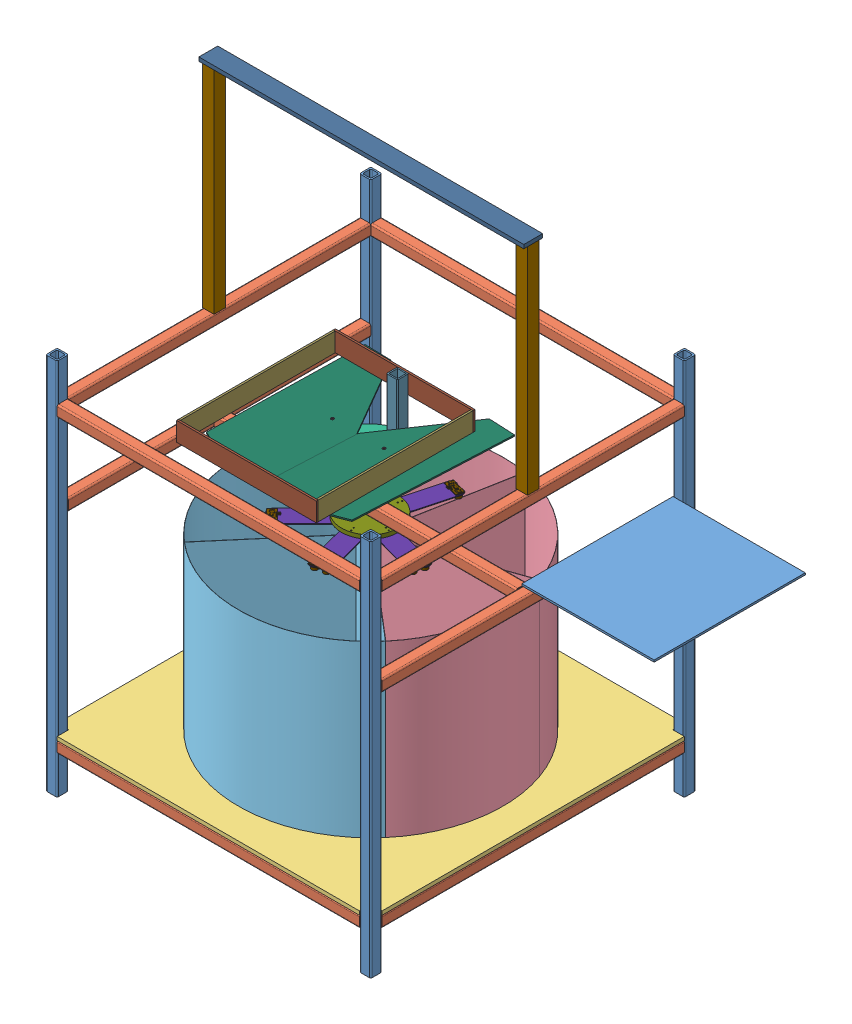
SolidWorks assembly Assem1, configuration Default. Lengths in mm.
Overall size (1243.66 1480 923.66).
50 component instances, 19 part files, 136 mates.
Components (placement in the parent):
- Bar_2-1: Bar_2 [Default] at (302.6173 -40.2152 847.0391) size (30 1000 30)
- Bar_2-2: Bar_2 [Default] at (302.6173 -40.2152 17.0391) size (30 1000 30)
- bar-2: bar [Default] at (1117.6173 74.7848 847.0391) x (0 1 0) z (0 0 1) size (30 800 30)
- Bar_2-5: Bar_2 [Default] at (1132.6173 -40.2152 847.0391) x (-1 0 0) z (0 0 -1) size (30 1000 30)
- bar-6: bar [Default] at (1132.6173 74.7848 32.0391) x (0 1 0) z (1 0 0) size (30 800 30)
- Bar_2-8: Bar_2 [Default] at (1132.6173 -40.2152 17.0391) x (0 0 1) z (-1 0 0) size (30 1000 30)
- bar-8: bar [Default] at (302.6173 74.7848 32.0391) x (0 -1 0) z (-1 0 0) size (30 800 30)
- bar-10: bar [Default] at (317.6173 74.7848 17.0391) x (0 1 0) z (0 0 -1) size (30 800 30)
- bar-12: bar [Default] at (317.6173 844.7848 847.0391) x (0 1 0) z (0 0 -1) size (30 800 30)
- bar-14: bar [Default] at (302.6173 844.7848 32.0391) x (0 1 0) z (1 0 0) size (30 800 30)
- bar-16: bar [Default] at (317.6173 844.7848 17.0391) x (0 1 0) z (0 0 -1) size (30 800 30)
- bar-18: bar [Default] at (1132.6173 844.7848 32.0391) x (0 1 0) z (1 0 0) size (30 800 30)
- bar-20: bar [Default] at (1117.6173 74.7848 287.0391) x (0 1 0) z (0 0 1) size (30 800 30)
- bar-22: bar [Default] at (1117.6173 74.7848 577.0391) x (0 -1 0) z (0 0 -1) size (30 800 30)
- bar-24: bar [Default] at (302.6173 614.7848 32.0391) x (0 1 0) z (1 0 0) size (30 800 30)
- bar-26: bar [Default] at (1132.6173 614.7848 832.0391) x (0 -1 0) z (1 0 0) size (30 800 30)
- sheet-1: sheet [Default] at (717.6173 89.7848 432.0391) size (860 10 860)
- Bin_Compart-1: Bin_Compart [Default] at (717.6173 99.7848 432.0391) x (0.181338 0 -0.983421) z (0.983421 0 0.181338) size (350.18 450 336.32)
- Bin_Compart-2: Bin_Compart [Default] at (717.6173 99.7848 432.0391) x (-0.942336 0 0.334667) z (-0.334667 0 -0.942336) size (350.18 450 336.32)
- Bin_Compart-3: Bin_Compart [Default] at (717.6173 99.7848 432.0391) x (-0.760999 0 -0.648753) z (0.648753 0 -0.760999) size (350.18 450 336.32)
- Part2-2: Part2 [Default] at (717.6173 99.7848 432.0391) x (-0.760999 0 -0.648753) z (0.648753 0 -0.760999) size (350.18 450 350.18)
- Disc-2: Disc [Default] at (716.3673 725.3848 433.2891) size (200 5 200)
- bar-27: bar [Default] at (317.6173 614.7848 432.0391) x (0 0 1) z (0 1 0) size (30 800 30)
- Stepper motor NEMA 23HS7430-1: Stepper motor NEMA 23HS7430 [По умолчанию] at (716.3673 709.7848 433.2891) x (1 0 0) z (0 -1 0) size (58.4 56.4 95.6)
- mount-1: mount [Default] at (742.6173 634.7848 457.0391) x (0 0 1) z (0 -1 0) size (50 50 5)
- bAR1-1: bAR1 [Default] at (1132.6173 1173.2848 432.0391) x (1 0 0) z (0 0 -1) size (30 570 30)
- bAR1-2: bAR1 [Default] at (302.6173 1173.2848 432.0391) x (1 0 0) z (0 0 -1) size (30 570 30)
- camera mount-1: camera mount [Default] at (287.6173 1439.7848 457.0391) x (0 0 -1) z (-1 0 0) size (50 10 860)
- Wall_1-1: Wall_1 [Default] at (530.859 829.3848 339.3531) x (0 -1 0) z (-1 0 0) size (50 5 370)
- wall_2-1: wall_2 [Default] at (535.859 879.3848 754.3531) x (1 0 0) z (0 0 -1) size (5 50 410)
- wall_2-2: wall_2 [Default] at (900.859 879.3848 754.3531) x (1 0 0) z (0 0 -1) size (5 50 410)
- Wall_1-2: Wall_1 [Default] at (900.859 829.3848 759.3531) x (0 -1 0) z (1 0 0) size (50 5 370)
- Part2-3: Part2 [Default] at (717.6173 99.7848 432.0391) x (0.648753 0 -0.760999) z (0.760999 0 0.648753) size (350.18 450 350.18)
- ft6560m 60kg.cm.step-5: ft6560m 60kg.cm.step [Default] at (784.8673 771.3848 446.4174) x (-1 0 0) z (0 0 -1) size (30 64 82)
- ft6560m 60kg.cm.step-6: ft6560m 60kg.cm.step [Default] at (647.8673 771.3848 446.4174) x (-1 0 0) z (0 0 -1) size (30 64 82)
- wall holder-2: wall holder [Default] at (715.859 879.3848 359.3531) x (0 0 -1) z (-1 0 0) size (30 150 30)
- flaps-3: flaps [Default] at (824.4567 792.4598 498.9645) x (-0.998861 0 -0.047712) z (0.047712 0 -0.998861) size (200 3.5 456.77)
- flaps-4: flaps [Default] at (605.9536 792.8098 496.1488) x (0.999772 0 0.021336) z (0.021336 0 -0.999772) size (200 3.5 456.77)
- UltraHolder-1: UltraHolder [Default] at (716.3673 589.7848 433.2891) x (-0.981254 0 0.19272) z (-0.19272 0 -0.981254) size (150 10 150)
- HC-SR04 Ultrasonic Sensor Holder-2: HC-SR04 Ultrasonic Sensor Holder [Default] at (733.5127 587.7848 594.4219) x (0 1 0) z (0.966613 0 -0.256242) size (2 150 50)
- HC-SR04 Ultrasonic Sensor Holder-3: HC-SR04 Ultrasonic Sensor Holder [Default] at (864.4113 587.7848 498.71) x (0 1 0) z (0.261394 0 -0.965232) size (2 150 50)
- HC-SR04 Ultrasonic Sensor Holder-4: HC-SR04 Ultrasonic Sensor Holder [Default] at (585.2984 587.7848 528.3994) x (0 1 0) z (0.705219 0 0.70899) size (2 150 50)
- HC-SR04 Ultrasonic Sensor Holder-5: HC-SR04 Ultrasonic Sensor Holder [Default] at (782.3211 587.7848 285.3868) x (0 1 0) z (-0.965232 0 -0.261394) size (2 150 50)
- HC-SR04 Ultrasonic Sensor Holder-7: HC-SR04 Ultrasonic Sensor Holder [Default] at (568.9979 587.7848 367.477) x (0 1 0) z (-0.261394 0 0.965232) size (2 150 50)
- HCSR04 Ultrasonic Sensor-1: HCSR04 Ultrasonic Sensor [Default] at (764.2023 591.2848 256.6516) x (-0.965232 0 -0.261394) z (0 -1 0) size (45 26.6 18)
- HCSR04 Ultrasonic Sensor-2: HCSR04 Ultrasonic Sensor [Default] at (540.2627 591.2848 385.5958) x (-0.261394 0 0.965232) z (0 -1 0) size (45 26.6 18)
- HCSR04 Ultrasonic Sensor-4: HCSR04 Ultrasonic Sensor [Default] at (586.6221 591.2848 562.3442) x (0.705219 0 0.70899) z (0 -1 0) size (45 26.6 18)
- HCSR04 Ultrasonic Sensor-6: HCSR04 Ultrasonic Sensor [Default] at (763.5715 591.2848 610.2479) x (0.966613 0 -0.256242) z (0 -1 0) size (45 26.6 18)
- HCSR04 Ultrasonic Sensor-8: HCSR04 Ultrasonic Sensor [Default] at (893.1465 591.2848 480.5912) x (0.261394 0 -0.965232) z (0 -1 0) size (45 26.6 18)
- electronic holder-1: electronic holder [Default] at (1310.1173 632.0348 212.0391) size (350 5 400)
Mates (geometry in assembly coordinates):
- Coincident1: coincident anti-aligned: plane of Bar_2-1 through (317.6173 959.7848 836.0391) normal (1 0 0); plane of bar-2 through (317.6173 85.7848 836.0391) normal (-1 0 0)
- Width1: width anti-aligned: plane of bar-2 through (317.6173 85.7848 862.0391) normal (0 0 1); plane of bar-2 through (317.6173 85.7848 832.0391) normal (0 0 -1); plane of Bar_2-1 through (313.6173 959.7848 832.0391) normal (0 0 -1); plane of Bar_2-1 through (313.6173 959.7848 862.0391) normal (0 0 1)
- Distance1: distance = 100 mm: line of bar-2 through (317.6173 59.7848 836.0391) axis (0 0 1); line of Bar_2-1 through (317.6173 -40.2152 858.0391) axis (0 0 -1)
- Coincident2: coincident anti-aligned: plane of bar-2 through (1117.6173 85.7848 836.0391) normal (1 0 0); plane of Bar_2-5 through (1117.6173 959.7848 858.0391) normal (-1 0 0)
- Width2: width anti-aligned: plane of bar-2 through (317.6173 85.7848 832.0391) normal (0 0 -1); plane of bar-2 through (317.6173 85.7848 862.0391) normal (0 0 1); plane of Bar_2-5 through (1121.6173 959.7848 862.0391) normal (0 0 1); plane of Bar_2-5 through (1121.6173 959.7848 832.0391) normal (0 0 -1)
- Distance2: distance = 100 mm: line of bar-2 through (1117.6173 59.7848 836.0391) axis (0 0 1); line of Bar_2-5 through (1117.6173 -40.2152 836.0391) axis (0 0 1)
- Coincident5: coincident anti-aligned: plane of Bar_2-5 through (1121.6173 959.7848 832.0391) normal (0 0 -1); plane of bar-6 through (1121.6173 85.7848 832.0391) normal (0 0 1)
- Width3: width anti-aligned: plane of bar-6 through (1147.6173 85.7848 832.0391) normal (1 0 0); plane of bar-6 through (1117.6173 85.7848 832.0391) normal (-1 0 0); plane of Bar_2-5 through (1117.6173 959.7848 858.0391) normal (-1 0 0); plane of Bar_2-5 through (1147.6173 959.7848 858.0391) normal (1 0 0)
- Distance3: distance = 100 mm: line of bar-6 through (1121.6173 59.7848 832.0391) axis (1 0 0); line of Bar_2-5 through (1143.6173 -40.2152 832.0391) axis (-1 0 0)
- Coincident6: coincident anti-aligned: plane of bar-6 through (1121.6173 85.7848 32.0391) normal (0 0 -1); plane of Bar_2-8 through (1143.6173 959.7848 32.0391) normal (0 0 1)
- Width4: width anti-aligned: plane of bar-6 through (1117.6173 85.7848 832.0391) normal (-1 0 0); plane of bar-6 through (1147.6173 85.7848 832.0391) normal (1 0 0); plane of Bar_2-8 through (1147.6173 959.7848 28.0391) normal (1 0 0); plane of Bar_2-8 through (1117.6173 959.7848 28.0391) normal (-1 0 0)
- Distance6: distance = 100 mm: line of Bar_2-8 through (1121.6173 -40.2152 32.0391) axis (1 0 0); line of bar-6 through (1121.6173 59.7848 32.0391) axis (1 0 0)
- Coincident8: coincident anti-aligned: plane of Bar_2-1 through (313.6173 959.7848 832.0391) normal (0 0 -1); plane of bar-8 through (313.6173 63.7848 832.0391) normal (0 0 1)
- Width5: width anti-aligned: plane of bar-8 through (287.6173 63.7848 832.0391) normal (-1 0 0); plane of bar-8 through (317.6173 63.7848 832.0391) normal (1 0 0); plane of Bar_2-1 through (317.6173 959.7848 836.0391) normal (1 0 0); plane of Bar_2-1 through (287.6173 959.7848 836.0391) normal (-1 0 0)
- Distance7: distance = 100 mm: line of bar-8 through (291.6173 59.7848 832.0391) axis (1 0 0); line of Bar_2-1 through (313.6173 -40.2152 832.0391) axis (-1 0 0)
- Coincident10: coincident anti-aligned: plane of Bar_2-2 through (313.6173 959.7848 32.0391) normal (0 0 1); plane of bar-8 through (313.6173 63.7848 32.0391) normal (0 0 -1)
- Width6: width anti-aligned: plane of bar-8 through (287.6173 63.7848 832.0391) normal (-1 0 0); plane of bar-8 through (317.6173 63.7848 832.0391) normal (1 0 0); plane of Bar_2-2 through (317.6173 959.7848 6.0391) normal (1 0 0); plane of Bar_2-2 through (287.6173 959.7848 6.0391) normal (-1 0 0)
- Distance8: distance = 100 mm: line of bar-8 through (291.6173 59.7848 32.0391) axis (1 0 0); line of Bar_2-2 through (291.6173 -40.2152 32.0391) axis (1 0 0)
- Coincident11: coincident anti-aligned: plane of Bar_2-8 through (1117.6173 959.7848 28.0391) normal (-1 0 0); plane of bar-10 through (1117.6173 85.7848 28.0391) normal (1 0 0)
- Width7: width anti-aligned: plane of bar-10 through (1117.6173 85.7848 2.0391) normal (0 0 -1); plane of bar-10 through (1117.6173 85.7848 32.0391) normal (0 0 1); plane of Bar_2-8 through (1143.6173 959.7848 32.0391) normal (0 0 1); plane of Bar_2-8 through (1143.6173 959.7848 2.0391) normal (0 0 -1)
- Distance9: distance = 100 mm: line of bar-10 through (1117.6173 59.7848 28.0391) axis (0 0 -1); line of Bar_2-8 through (1117.6173 -40.2152 6.0391) axis (0 0 1)
- Coincident14: coincident anti-aligned: plane of Bar_2-5 through (1117.6173 959.7848 858.0391) normal (-1 0 0); plane of bar-12 through (1117.6173 855.7848 858.0391) normal (1 0 0)
- Width9: width anti-aligned: plane of bar-12 through (1117.6173 855.7848 832.0391) normal (0 0 -1); plane of Bar_2-5 through (1117.6173 855.7848 862.0391) normal (0 0 1); plane of bar-12 through (1121.6173 959.7848 862.0391) normal (0 0 1); plane of Bar_2-5 through (1121.6173 959.7848 832.0391) normal (0 0 -1)
- Distance11: distance = 100 mm: line of bar-12 through (1117.6173 859.7848 836.0391) axis (0 0 1); line of Bar_2-5 through (1117.6173 959.7848 836.0391) axis (0 0 1)
- Coincident15: coincident anti-aligned: plane of Bar_2-1 through (313.6173 959.7848 832.0391) normal (0 0 -1); plane of bar-14 through (291.6173 855.7848 832.0391) normal (0 0 1)
- Width10: width anti-aligned: plane of bar-14 through (317.6173 855.7848 832.0391) normal (1 0 0); plane of Bar_2-1 through (287.6173 855.7848 832.0391) normal (-1 0 0); plane of bar-14 through (287.6173 959.7848 836.0391) normal (-1 0 0); plane of Bar_2-1 through (317.6173 959.7848 836.0391) normal (1 0 0)
- Distance12: distance = 100 mm: line of bar-14 through (313.6173 859.7848 832.0391) axis (-1 0 0); line of Bar_2-1 through (313.6173 959.7848 832.0391) axis (-1 0 0)
- Coincident16: coincident anti-aligned: plane of Bar_2-8 through (1117.6173 959.7848 28.0391) normal (-1 0 0); plane of bar-16 through (1117.6173 855.7848 28.0391) normal (1 0 0)
- Width11: width anti-aligned: plane of bar-16 through (1117.6173 855.7848 2.0391) normal (0 0 -1); plane of Bar_2-8 through (1117.6173 855.7848 32.0391) normal (0 0 1); plane of bar-16 through (1143.6173 959.7848 32.0391) normal (0 0 1); plane of Bar_2-8 through (1143.6173 959.7848 2.0391) normal (0 0 -1)
- Distance14: distance = 100 mm: point of bar-16; line of Bar_2-8 through (1117.6173 959.7848 6.0391) axis (0 0 1)
- Coincident18: coincident anti-aligned: plane of Bar_2-5 through (1121.6173 959.7848 832.0391) normal (0 0 -1); plane of bar-18 through (1121.6173 855.7848 832.0391) normal (0 0 1)
- Width13: width anti-aligned: plane of bar-18 through (1147.6173 855.7848 832.0391) normal (1 0 0); plane of Bar_2-5 through (1117.6173 855.7848 832.0391) normal (-1 0 0); plane of bar-18 through (1117.6173 959.7848 858.0391) normal (-1 0 0); plane of Bar_2-5 through (1147.6173 959.7848 858.0391) normal (1 0 0)
- Distance15: distance = 100 mm: line of bar-18 through (1143.6173 859.7848 832.0391) axis (-1 0 0); line of Bar_2-5 through (1143.6173 959.7848 832.0391) axis (-1 0 0)
- Coincident20: coincident anti-aligned: plane of bar-8 through (317.6173 63.7848 832.0391) normal (1 0 0); plane of bar-20 through (317.6173 85.7848 276.0391) normal (-1 0 0)
- Width15: width aligned: plane of bar-20 through (317.6173 89.7848 276.0391) normal (0 1 0); plane of bar-8 through (317.6173 59.7848 276.0391) normal (0 -1 0); plane of bar-20 through (313.6173 89.7848 832.0391) normal (0 1 0); plane of bar-8 through (313.6173 59.7848 832.0391) normal (0 -1 0)
- Distance17: distance = 240 mm anti-aligned: plane of bar-20 through (317.6173 85.7848 272.0391) normal (0 0 -1); plane of bar-10 through (1117.6173 85.7848 32.0391) normal (0 0 1)
- Coincident21: coincident anti-aligned: plane of bar-8 through (317.6173 63.7848 832.0391) normal (1 0 0); plane of bar-22 through (317.6173 63.7848 588.0391) normal (-1 0 0)
- Width16: width aligned: plane of bar-22 through (317.6173 59.7848 588.0391) normal (0 -1 0); plane of bar-8 through (317.6173 89.7848 588.0391) normal (0 1 0); plane of bar-22 through (313.6173 89.7848 832.0391) normal (0 1 0); plane of bar-8 through (313.6173 59.7848 832.0391) normal (0 -1 0)
- Distance18: distance = 240 mm anti-aligned: plane of bar-22 through (317.6173 63.7848 592.0391) normal (0 0 1); plane of bar-2 through (317.6173 85.7848 832.0391) normal (0 0 -1)
- Coincident23: coincident anti-aligned: plane of Bar_2-1 through (313.6173 959.7848 832.0391) normal (0 0 -1); plane of bar-24 through (291.6173 625.7848 832.0391) normal (0 0 1)
- Width18: width anti-aligned: plane of bar-24 through (317.6173 625.7848 832.0391) normal (1 0 0); plane of Bar_2-1 through (287.6173 625.7848 832.0391) normal (-1 0 0); plane of bar-24 through (287.6173 959.7848 836.0391) normal (-1 0 0); plane of Bar_2-1 through (317.6173 959.7848 836.0391) normal (1 0 0)
- Distance19: distance = 200 mm anti-aligned: plane of bar-24 through (291.6173 629.7848 832.0391) normal (0 1 0); plane of bar-14 through (291.6173 829.7848 832.0391) normal (0 -1 0)
- Coincident26: coincident anti-aligned: plane of Bar_2-8 through (1143.6173 959.7848 32.0391) normal (0 0 1); plane of bar-26 through (1121.6173 603.7848 32.0391) normal (0 0 -1)
- Width20: width anti-aligned: plane of bar-26 through (1147.6173 603.7848 32.0391) normal (1 0 0); plane of Bar_2-8 through (1117.6173 603.7848 32.0391) normal (-1 0 0); plane of bar-26 through (1117.6173 959.7848 28.0391) normal (-1 0 0); plane of Bar_2-8 through (1147.6173 959.7848 28.0391) normal (1 0 0)
- Distance20: distance = 200 mm anti-aligned: plane of bar-26 through (1121.6173 629.7848 32.0391) normal (0 1 0); plane of bar-18 through (1121.6173 829.7848 832.0391) normal (0 -1 0)
- Coincident28: coincident anti-aligned: plane of Bar_2-5 through (1121.6173 959.7848 832.0391) normal (0 0 -1); plane of sheet-1 through (717.6173 99.7848 832.0391) normal (0 0 1)
- Coincident29: coincident anti-aligned: plane of bar-6 through (1121.6173 89.7848 832.0391) normal (0 1 0); plane of sheet-1 through (717.6173 89.7848 432.0391) normal (0 -1 0)
- Coincident30: coincident anti-aligned: plane of Bar_2-5 through (1117.6173 959.7848 858.0391) normal (-1 0 0); plane of sheet-1 through (1117.6173 99.7848 432.0391) normal (1 0 0)
- Coincident34: coincident anti-aligned: plane of sheet-1 through (717.6173 99.7848 432.0391) normal (0 1 0); plane of Bin_Compart-1 through (717.6173 99.7848 432.0391) normal (0 -1 0)
- Coincident35: coincident anti-aligned: plane of sheet-1 through (717.6173 99.7848 432.0391) normal (0 1 0); plane of Bin_Compart-3 through (717.6173 99.7848 432.0391) normal (0 -1 0)
- Coincident36: coincident anti-aligned: plane of sheet-1 through (717.6173 99.7848 432.0391) normal (0 1 0); plane of Bin_Compart-2 through (717.6173 99.7848 432.0391) normal (0 -1 0)
- Coincident39: coincident anti-aligned: plane of sheet-1 through (717.6173 99.7848 432.0391) normal (0 1 0); plane of Part2-2 through (717.6173 99.7848 432.0391) normal (0 -1 0)
- ProfileCenter1: profile center anti-aligned: plane of bar-27 through (1117.6173 603.7848 443.0391) normal (1 0 0); plane of bar-26 through (1117.6173 603.7848 32.0391) normal (-1 0 0)
- ProfileCenter2: profile center anti-aligned: plane of mount-1 through (742.6173 629.7848 457.0391) normal (0 -1 0); plane of bar-27 through (1117.6173 629.7848 443.0391) normal (0 1 0)
- Coincident55: coincident anti-aligned: plane of Stepper motor NEMA 23HS7430-1 through (739.9173 634.7848 409.7391) normal (0 -1 0); plane of mount-1 through (742.6173 634.7848 457.0391) normal (0 1 0)
- Concentric1: concentric anti-aligned: cylinder of Stepper motor NEMA 23HS7430-1 through (739.9173 709.7848 409.7391) axis (0 -1 0) radius 2.5; cylinder of mount-1 through (739.9173 629.7848 409.7391) axis (0 1 0) radius 1.25
- ProfileCenter3: profile center aligned: plane of Disc-2 through (716.3673 730.3848 433.2891) normal (0 1 0); plane of Stepper motor NEMA 23HS7430-1 through (716.3673 730.3848 433.2891) normal (0 1 0)
- ProfileCenter6: profile center anti-aligned: plane of bAR1-1 through (1132.6173 859.7848 432.0391) normal (0 -1 0); plane of bar-18 through (1121.6173 859.7848 832.0391) normal (0 1 0)
- ProfileCenter7: profile center anti-aligned: plane of bAR1-2 through (302.6173 859.7848 432.0391) normal (0 -1 0); plane of bar-14 through (291.6173 859.7848 832.0391) normal (0 1 0)
- Coincident63: coincident aligned: line of bAR1-1 through (1147.6173 1429.7848 417.0391) axis (0 0 1); line of camera mount-1 through (1147.6173 1429.7848 407.0391) axis (0 0 1)
- Coincident64: coincident anti-aligned: plane of bAR1-1 through (1132.6173 1429.7848 432.0391) normal (0 1 0); plane of camera mount-1 through (287.6173 1429.7848 457.0391) normal (0 -1 0)
- Width21: width anti-aligned: plane of bAR1-2 through (317.6173 859.7848 417.0391) normal (0 0 -1); plane of bAR1-2 through (317.6173 859.7848 447.0391) normal (0 0 1); plane of camera mount-1 through (1147.6173 1429.7848 457.0391) normal (0 0 1); plane of camera mount-1 through (287.6173 1429.7848 407.0391) normal (0 0 -1)
- Parallel7: parallel anti-aligned: cylinder of Stepper motor NEMA 23HS7430-1 through (732.5673 636.7848 458.7391) axis (0 -1 0) radius 1.25; cylinder of mount-1 through (695.3173 629.7848 409.7391) axis (0 1 0) radius 1.25
- Parallel12: parallel aligned: line of Stepper motor NEMA 23HS7430-1 through (732.4173 634.7848 460.9891) axis (-1 0 0); line of mount-1 through (742.6173 634.7848 457.0391) axis (-1 0 0)
- Coincident75: coincident anti-aligned: line of Wall_1-1 through (530.859 829.3848 344.3531) axis (1 0 0); line of wall_2-1 through (535.859 829.3848 344.3531) axis (-1 0 0)
- Coincident76: coincident anti-aligned: line of Wall_1-1 through (530.859 879.3848 344.3531) axis (0 -1 0); line of wall_2-1 through (530.859 829.3848 344.3531) axis (0 1 0)
- Coincident77: coincident anti-aligned: line of Wall_1-1 through (530.859 829.3848 344.3531) axis (1 0 0); line of wall_2-2 through (900.859 829.3848 344.3531) axis (-1 0 0)
- Coincident78: coincident anti-aligned: line of Wall_1-1 through (900.859 829.3848 344.3531) axis (0 1 0); line of wall_2-2 through (900.859 879.3848 344.3531) axis (0 -1 0)
- Coincident82: coincident aligned: line of wall_2-2 through (900.859 829.3848 754.3531) axis (-1 0 0); line of Wall_1-2 through (900.859 829.3848 754.3531) axis (-1 0 0)
- Coincident83: coincident aligned: line of wall_2-2 through (900.859 879.3848 754.3531) axis (0 -1 0); line of Wall_1-2 through (900.859 879.3848 754.3531) axis (0 -1 0)
- Coincident84: coincident aligned: line of wall_2-1 through (535.859 829.3848 754.3531) axis (-1 0 0); line of Wall_1-2 through (900.859 829.3848 754.3531) axis (-1 0 0)
- Coincident85: coincident anti-aligned: plane of Part2-2 through (717.6173 549.7848 432.0391) normal (-0.760999 0 -0.648753); plane of Part2-3 through (717.6173 549.7848 432.0391) normal (0.760999 0 0.648753)
- Coincident86: coincident anti-aligned: plane of sheet-1 through (717.6173 99.7848 432.0391) normal (0 1 0); plane of Part2-3 through (717.6173 99.7848 432.0391) normal (0 -1 0)
- Coincident87: coincident aligned: line of Part2-2 through (490.44 549.7848 698.5218) axis (0 -1 0); line of Part2-3 through (490.44 549.7848 698.5218) axis (0 -1 0)
- Coincident88: coincident anti-aligned: plane of Bin_Compart-2 through (720.5187 549.7848 416.3044) normal (0.983421 0 0.181338); plane of Bin_Compart-3 through (781.1172 549.7848 87.6697) normal (-0.983421 0 -0.181338)
- Coincident89: coincident aligned: line of Bin_Compart-2 through (781.1172 549.7848 87.6697) axis (0 -1 0); line of Bin_Compart-3 through (781.1172 549.7848 87.6697) axis (0 -1 0)
- Coincident90: coincident anti-aligned: plane of Bin_Compart-1 through (1047.5999 549.7848 314.847) normal (-0.334667 0 -0.942336); plane of Bin_Compart-3 through (732.6946 549.7848 426.6845) normal (0.334667 0 0.942336)
- Coincident91: coincident aligned: line of Bin_Compart-1 through (1047.5999 549.7848 314.847) axis (0 -1 0); line of Bin_Compart-3 through (1047.5999 549.7848 314.847) axis (0 -1 0)
- Coincident92: coincident aligned: line of Bin_Compart-1 through (984.1 549.7848 659.2164) axis (0 -1 0); line of Part2-2 through (984.1 549.7848 659.2164) axis (0 -1 0)
- Coincident93: coincident aligned: line of Bin_Compart-2 through (451.1346 549.7848 204.8619) axis (0 -1 0); line of Part2-3 through (451.1346 549.7848 204.8619) axis (0 -1 0)
- Concentric20: concentric anti-aligned: cylinder of sheet-1 through (717.6173 89.7848 432.0391) axis (0 1 0) radius 1; cylinder of Part2-2 through (717.6173 549.7848 432.0391) axis (0 -1 0) radius 27.5
- Concentric22: concentric anti-aligned: cylinder of Disc-2 through (776.3673 720.3848 409.4174) axis (0 1 0) radius 2.5; cylinder of ft6560m 60kg.cm.step-5 through (776.3673 775.3848 409.4174) axis (0 -1 0) radius 2.5
- Concentric23: concentric anti-aligned: cylinder of Disc-2 through (793.3673 720.3848 409.4174) axis (0 1 0) radius 2.5; cylinder of ft6560m 60kg.cm.step-5 through (793.3673 775.3848 409.4174) axis (0 -1 0) radius 2.5
- Coincident94: coincident anti-aligned: plane of Disc-2 through (716.3673 730.3848 433.2891) normal (0 1 0); plane of ft6560m 60kg.cm.step-5 through (784.8673 730.3848 446.4174) normal (0 -1 0)
- Coincident96: coincident anti-aligned: plane of Disc-2 through (716.3673 730.3848 433.2891) normal (0 1 0); plane of ft6560m 60kg.cm.step-6 through (647.8673 730.3848 446.4174) normal (0 -1 0)
- Concentric31: concentric anti-aligned: cylinder of Disc-2 through (776.3673 720.3848 483.4174) axis (0 1 0) radius 2.5; cylinder of ft6560m 60kg.cm.step-5 through (776.3673 775.3848 483.4174) axis (0 -1 0) radius 2.5
- Concentric34: concentric anti-aligned: cylinder of Disc-2 through (656.3673 720.3848 409.4174) axis (0 1 0) radius 2.5; cylinder of ft6560m 60kg.cm.step-6 through (656.3673 775.3848 409.4174) axis (0 -1 0) radius 2.5
- Concentric35: concentric anti-aligned: cylinder of Disc-2 through (639.3673 720.3848 483.4174) axis (0 1 0) radius 2.5; cylinder of ft6560m 60kg.cm.step-6 through (639.3673 775.3848 483.4174) axis (0 -1 0) radius 2.5
- Coincident97: coincident anti-aligned: plane of Disc-2 through (716.3673 729.3848 433.2891) normal (0 1 0); plane of wall holder-2 through (727.859 729.3848 347.3531) normal (0 -1 0)
- Coincident98: coincident anti-aligned: line of Disc-2 through (700.859 729.3848 344.3531) axis (0 0 1); line of wall holder-2 through (700.859 729.3848 371.3531) axis (0 0 -1)
- Coincident99: coincident anti-aligned: line of Disc-2 through (730.859 729.3848 344.3531) axis (-1 0 0); line of wall holder-2 through (703.859 729.3848 344.3531) axis (1 0 0)
- Coincident102: coincident anti-aligned: line of Wall_1-1 through (900.859 879.3848 344.3531) axis (-1 0 0); line of wall holder-2 through (703.859 879.3848 344.3531) axis (1 0 0)
- Width22: width anti-aligned: plane of wall_2-2 through (895.859 829.3848 344.3531) normal (-1 0 0); plane of wall holder-2 through (535.859 879.3848 344.3531) normal (1 0 0); plane of wall_2-1 through (730.859 729.3848 347.3531) normal (1 0 0); plane of wall holder-2 through (700.859 729.3848 347.3531) normal (-1 0 0)
- Concentric36: concentric aligned: cylinder of ft6560m 60kg.cm.step-6 through (647.8673 794.3848 463.9174) axis (0 -1 0) radius 4; cylinder of flaps-4 through (647.8673 794.3848 463.9174) axis (0 -1 0) radius 4
- Coincident108: coincident anti-aligned: plane of Wall_1-1 through (530.859 829.3848 344.3531) normal (0 0 1); plane of wall holder-2 through (727.859 729.3848 344.3531) normal (0 0 -1)
- Coincident110: coincident anti-aligned: circle of ft6560m 60kg.cm.step-6; circle of flaps-4
- Coincident111: coincident aligned: circle of ft6560m 60kg.cm.step-5; circle of flaps-3
- Concentric37: concentric aligned: cylinder of Stepper motor NEMA 23HS7430-1 through (716.3673 730.3848 433.2891) axis (0 -1 0) radius 3.175; cylinder of UltraHolder-1 through (716.3673 599.7848 433.2891) axis (0 -1 0) radius 5
- Coincident113: coincident anti-aligned: plane of bar-27 through (1117.6173 599.7848 443.0391) normal (0 -1 0); plane of UltraHolder-1 through (716.3673 599.7848 433.2891) normal (0 1 0)
- Concentric39: concentric anti-aligned: cylinder of UltraHolder-1 through (774.4229 589.7848 448.4398) axis (0 1 0) radius 1.5; cylinder of HC-SR04 Ultrasonic Sensor Holder-3 through (774.4229 589.7848 448.4398) axis (0 -1 0) radius 1.5
- Concentric40: concentric anti-aligned: cylinder of UltraHolder-1 through (784.0752 589.7848 451.0537) axis (0 1 0) radius 1.5; cylinder of HC-SR04 Ultrasonic Sensor Holder-3 through (784.0752 589.7848 451.0537) axis (0 -1 0) radius 1.5
- Coincident119: coincident anti-aligned: plane of UltraHolder-1 through (716.3673 589.7848 433.2891) normal (0 -1 0); plane of HC-SR04 Ultrasonic Sensor Holder-3 through (766.4793 589.7848 420.3881) normal (0 1 0)
- Concentric41: concentric anti-aligned: cylinder of UltraHolder-1 through (732.0537 589.7848 491.3546) axis (0 1 0) radius 1.5; cylinder of HC-SR04 Ultrasonic Sensor Holder-2 through (732.0537 589.7848 491.3546) axis (0 -1 0) radius 1.5
- Concentric42: concentric anti-aligned: cylinder of UltraHolder-1 through (734.6161 589.7848 501.0207) axis (0 1 0) radius 1.5; cylinder of HC-SR04 Ultrasonic Sensor Holder-2 through (734.6161 589.7848 501.0207) axis (0 -1 0) radius 1.5
- Coincident120: coincident anti-aligned: plane of UltraHolder-1 through (716.3673 589.7848 433.2891) normal (0 -1 0); plane of HC-SR04 Ultrasonic Sensor Holder-2 through (752.3754 589.7848 470.4493) normal (0 1 0)
- Concentric43: concentric anti-aligned: cylinder of UltraHolder-1 through (673.8279 589.7848 475.6023) axis (0 1 0) radius 1.5; cylinder of HC-SR04 Ultrasonic Sensor Holder-4 through (673.8279 589.7848 475.6023) axis (0 -1 0) radius 1.5
- Concentric44: concentric anti-aligned: cylinder of UltraHolder-1 through (666.738 589.7848 482.6545) axis (0 1 0) radius 1.5; cylinder of HC-SR04 Ultrasonic Sensor Holder-4 through (666.738 589.7848 482.6545) axis (0 -1 0) radius 1.5
- Concentric45: concentric anti-aligned: cylinder of UltraHolder-1 through (673.8279 589.7848 475.6023) axis (0 1 0) radius 1.5; cylinder of HC-SR04 Ultrasonic Sensor Holder-4 through (673.8279 589.7848 475.6023) axis (0 -1 0) radius 1.5
- Coincident121: coincident anti-aligned: plane of UltraHolder-1 through (716.3673 589.7848 433.2891) normal (0 -1 0); plane of HC-SR04 Ultrasonic Sensor Holder-4 through (702.0932 589.7848 482.7487) normal (0 1 0)
- Concentric46: concentric anti-aligned: cylinder of UltraHolder-1 through (732.0509 589.7848 375.3752) axis (0 1 0) radius 1.5; cylinder of HC-SR04 Ultrasonic Sensor Holder-5 through (732.0509 589.7848 375.3752) axis (0 -1 0) radius 1.5
- Concentric47: concentric anti-aligned: cylinder of UltraHolder-1 through (732.0509 589.7848 375.3752) axis (0 1 0) radius 1.5; cylinder of HC-SR04 Ultrasonic Sensor Holder-5 through (732.0509 589.7848 375.3752) axis (0 -1 0) radius 1.5
- Concentric48: concentric anti-aligned: cylinder of UltraHolder-1 through (734.6648 589.7848 365.7229) axis (0 1 0) radius 1.5; cylinder of HC-SR04 Ultrasonic Sensor Holder-5 through (734.6648 589.7848 365.7229) axis (0 -1 0) radius 1.5
- Coincident123: coincident anti-aligned: plane of UltraHolder-1 through (716.3673 589.7848 433.2891) normal (0 -1 0); plane of HC-SR04 Ultrasonic Sensor Holder-5 through (703.9992 589.7848 383.3188) normal (0 1 0)
- Concentric54: concentric anti-aligned: cylinder of UltraHolder-1 through (658.9863 589.7848 417.7472) axis (0 1 0) radius 1.5; cylinder of HC-SR04 Ultrasonic Sensor Holder-7 through (658.9863 589.7848 417.7472) axis (0 -1 0) radius 1.5
- Concentric55: concentric anti-aligned: cylinder of UltraHolder-1 through (658.9863 589.7848 417.7472) axis (0 1 0) radius 1.5; cylinder of HC-SR04 Ultrasonic Sensor Holder-7 through (658.9863 589.7848 417.7472) axis (0 -1 0) radius 1.5
- Concentric56: concentric anti-aligned: cylinder of UltraHolder-1 through (649.334 589.7848 415.1333) axis (0 1 0) radius 1.5; cylinder of HC-SR04 Ultrasonic Sensor Holder-7 through (649.334 589.7848 415.1333) axis (0 -1 0) radius 1.5
- Coincident125: coincident anti-aligned: plane of UltraHolder-1 through (716.3673 589.7848 433.2891) normal (0 -1 0); plane of HC-SR04 Ultrasonic Sensor Holder-7 through (666.9299 589.7848 445.7989) normal (0 1 0)
- Concentric57: concentric aligned: cylinder of HC-SR04 Ultrasonic Sensor Holder-5 through (776.7503 539.7848 260.0498) axis (0 1 0) radius 8.1; cylinder of HCSR04 Ultrasonic Sensor-1 through (776.7503 577.7848 260.0498) axis (0 1 0) radius 8
- Concentric58: concentric aligned: cylinder of HC-SR04 Ultrasonic Sensor Holder-5 through (751.6543 539.7848 253.2535) axis (0 1 0) radius 8.1; cylinder of HCSR04 Ultrasonic Sensor-1 through (751.6543 577.7848 253.2535) axis (0 1 0) radius 8
- Coincident126: coincident anti-aligned: plane of HC-SR04 Ultrasonic Sensor Holder-5 through (703.9992 589.7848 383.3188) normal (0 1 0); plane of HCSR04 Ultrasonic Sensor-1 through (764.2023 589.7848 256.6516) normal (0 -1 0)
- Concentric59: concentric aligned: cylinder of HC-SR04 Ultrasonic Sensor Holder-7 through (543.6609 539.7848 373.0478) axis (0 1 0) radius 8.1; cylinder of HCSR04 Ultrasonic Sensor-2 through (543.6609 577.7848 373.0478) axis (0 1 0) radius 8
- Concentric60: concentric aligned: cylinder of HC-SR04 Ultrasonic Sensor Holder-7 through (536.8646 539.7848 398.1438) axis (0 1 0) radius 8.1; cylinder of HCSR04 Ultrasonic Sensor-2 through (536.8646 577.7848 398.1438) axis (0 1 0) radius 8
- Coincident127: coincident anti-aligned: plane of HC-SR04 Ultrasonic Sensor Holder-7 through (666.9299 589.7848 445.7989) normal (0 1 0); plane of HCSR04 Ultrasonic Sensor-2 through (540.2627 589.7848 385.5958) normal (0 -1 0)
- Concentric61: concentric aligned: cylinder of HC-SR04 Ultrasonic Sensor Holder-4 through (577.4543 539.7848 553.1273) axis (0 1 0) radius 8.1; cylinder of HCSR04 Ultrasonic Sensor-4 through (577.4543 577.7848 553.1273) axis (0 1 0) radius 8
- Concentric62: concentric aligned: cylinder of HC-SR04 Ultrasonic Sensor Holder-4 through (595.79 539.7848 571.561) axis (0 1 0) radius 8.1; cylinder of HCSR04 Ultrasonic Sensor-4 through (595.79 577.7848 571.561) axis (0 1 0) radius 8
- Coincident128: coincident anti-aligned: plane of HC-SR04 Ultrasonic Sensor Holder-4 through (702.0932 589.7848 482.7487) normal (0 1 0); plane of HCSR04 Ultrasonic Sensor-4 through (586.6221 589.7848 562.3442) normal (0 -1 0)
- Concentric63: concentric aligned: cylinder of HC-SR04 Ultrasonic Sensor Holder-2 through (751.0056 539.7848 613.579) axis (0 1 0) radius 8.1; cylinder of HCSR04 Ultrasonic Sensor-6 through (751.0056 577.7848 613.579) axis (0 1 0) radius 8
- Concentric64: concentric aligned: cylinder of HC-SR04 Ultrasonic Sensor Holder-2 through (776.1375 539.7848 606.9167) axis (0 1 0) radius 8.1; cylinder of HCSR04 Ultrasonic Sensor-6 through (776.1375 577.7848 606.9167) axis (0 1 0) radius 8
- Coincident129: coincident anti-aligned: plane of HC-SR04 Ultrasonic Sensor Holder-2 through (752.3754 589.7848 470.4493) normal (0 1 0); plane of HCSR04 Ultrasonic Sensor-6 through (763.5715 589.7848 610.2479) normal (0 -1 0)
- Concentric65: concentric aligned: cylinder of HC-SR04 Ultrasonic Sensor Holder-3 through (889.7483 539.7848 493.1393) axis (0 1 0) radius 8.1; cylinder of HCSR04 Ultrasonic Sensor-8 through (889.7483 577.7848 493.1393) axis (0 1 0) radius 8
- Concentric66: concentric aligned: cylinder of HC-SR04 Ultrasonic Sensor Holder-3 through (896.5446 539.7848 468.0432) axis (0 1 0) radius 8.1; cylinder of HCSR04 Ultrasonic Sensor-8 through (896.5446 577.7848 468.0432) axis (0 1 0) radius 8
- Coincident130: coincident anti-aligned: plane of HC-SR04 Ultrasonic Sensor Holder-3 through (766.4793 589.7848 420.3881) normal (0 1 0); plane of HCSR04 Ultrasonic Sensor-8 through (893.1465 589.7848 480.5912) normal (0 -1 0)
- Coincident131: coincident anti-aligned: plane of bar-26 through (1121.6173 629.7848 32.0391) normal (0 1 0); plane of electronic holder-1 through (1467.6173 629.7848 32.0391) normal (0 -1 0)
- Coincident132: coincident anti-aligned: plane of Bar_2-8 through (1143.6173 959.7848 32.0391) normal (0 0 1); plane of electronic holder-1 through (1467.6173 634.7848 32.0391) normal (0 0 -1)
- Coincident133: coincident aligned: plane of bar-26 through (1117.6173 603.7848 32.0391) normal (-1 0 0); plane of electronic holder-1 through (1117.6173 634.7848 32.0391) normal (-1 0 0)
- Parallel13: parallel aligned: plane of Wall_1-2 through (900.859 829.3848 759.3531) normal (0 0 1)
